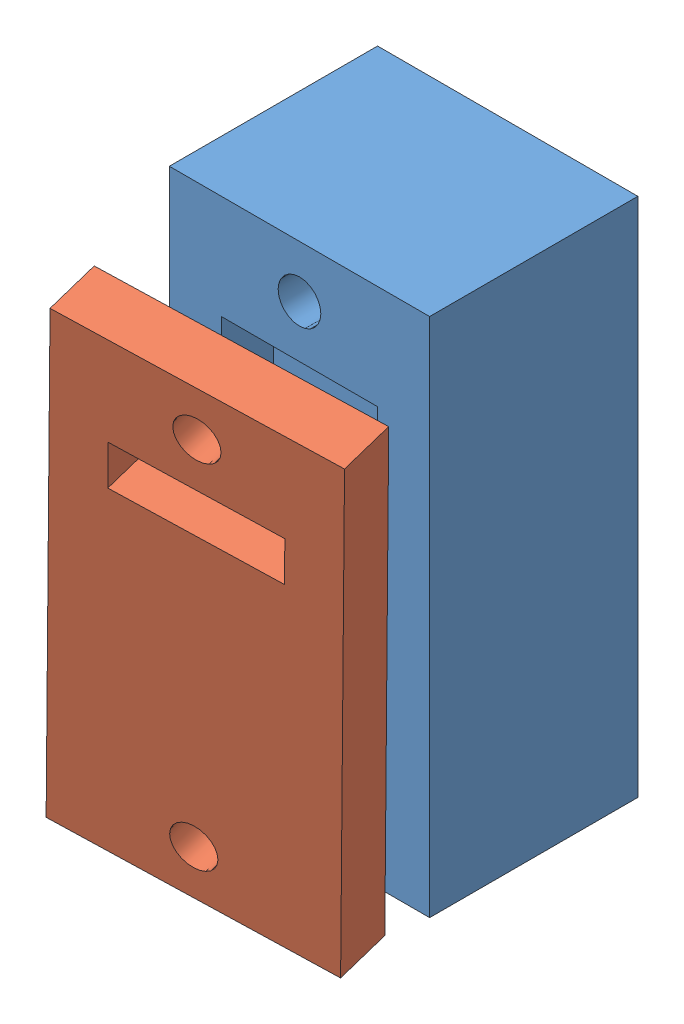
SolidWorks assembly Assem1, configuration Default. Lengths in mm.
Overall size (17.32 27.96 18.04).
2 component instances, 2 part files, 0 mates.
Components (placement in the parent):
- New_chompy_thingy-1: New_chompy_thingy [Default] at (8.9126 22.578 -8.0532) size (12.7 25.4 10.16)
- Newest_top_of_sabrina-1: Newest_top_of_sabrina [Default] at (9.0958 33.7251 2.2915) x (-0.138671 -0.981616 -0.131153) z (0.981579 -0.118659 -0.149739) size (25.4 10.16 12.7)
